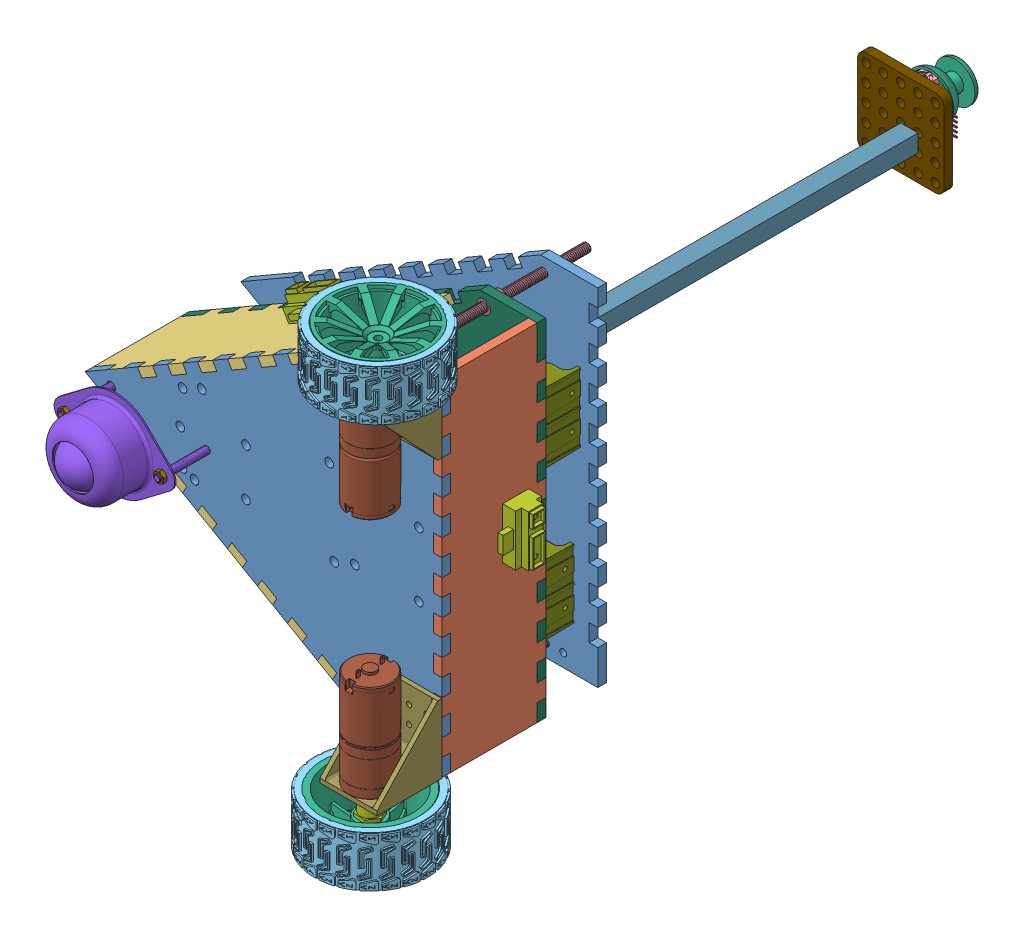
SolidWorks assembly Assembly File_R01, configuration Default. Lengths in mm.
Overall size (224.4 260.03 452.74).
51 component instances, 27 part files, 75 mates.
Components (placement in the parent):
- triangular base 1-1: triangular base 1 [Default] at (154.8111 203.7551 170.4098) size (206.21 200 5)
- the back wall-1: the back wall [Default] at (152.3111 203.7551 170.4098) x (1 0 0) z (0 1 0) size (5 60 200)
- Walls-1: Walls [Default] at (-31.5732 93.7549 170.4098) x (0.866025 -0.5 0) z (0.5 0.866025 0) size (180 60 5)
- Walls-2: Walls [Default] at (-46.394 99.4249 170.4098) x (0.866025 0.5 0) z (-0.5 0.866025 0) size (180 60 5)
- ArduinoMega2560-1: ArduinoMega2560 [Predeterminado] at (124.9198 138.7551 169.4098) x (0 1 0) z (-1 0 0) size (100 11.65 51.63)
- blue_wheel_with_adapter-1: blue_wheel_with_adapter [Default] at (122.4376 180.4937 248.1171) x (1 0 0) z (0 1 0) size (69.31 69.31 29.8)
  - 65mm tire-1: 65mm tire [Default] at (18.1044 52.2783 38.5614) x (-0.068419 0.997657 0) z (0 0 1) size (65.01 65.01 29)
  - blue_wheel_frame-2: blue_wheel_frame [Default] at (18.0756 52.6985 38.5614) x (0 0 -1) z (-0.994893 -0.10093 0) size (29 56 56)
  - motor_adapter-1: motor_adapter [Default] at (18.0661 52.7117 35.2614) x (0.583313 -0.812247 0) z (0 0 1) size (13.7 12 18.23)
- blue_wheel_with_adapter-2: blue_wheel_with_adapter [Default] at (122.7449 26.5815 147.6981) x (1 0 0) z (0 -1 0) size (69.31 69.31 29.8)
  - 65mm tire-1: 65mm tire [Default] at (18.1044 52.2783 38.5614) x (-0.068419 0.997657 0) z (0 0 1) size (65.01 65.01 29)
  - blue_wheel_frame-2: blue_wheel_frame [Default] at (18.0756 52.6985 38.5614) x (0 0 -1) z (-0.994893 -0.10093 0) size (29 56 56)
  - motor_adapter-1: motor_adapter [Default] at (18.0661 52.7117 35.2614) x (0.583313 -0.812247 0) z (0 0 1) size (13.7 12 18.23)
- Flange-Mount Ball Transfer-1: Flange-Mount Ball Transfer [Default] at (-6.1792 101.835 201.1718) x (0.069114 0.997609 0) z (-0.997609 0.069114 0) size (50.8 30.16 69.85)
- l298n1-1: l298n1 [Default] at (23.2111 102.2551 170.4098) x (0 -1 0) z (0 0 -1) size (43 43 26.5)
- MiniBreadboard-1: MiniBreadboard [Default] at (129.5111 61.4551 170.4098) x (0 1 0) z (-1 0 0) size (34.6 8.15 45.6)
- JGA25-372 24V Motor-1: JGA25-372 24V Motor [Ratio 171 & 226] at (140.8111 5.8202 200.4098) x (0 0 -1) z (-1 0 0) size (25.02 71.1 25)
- JGA25-372 24V Motor-2: JGA25-372 24V Motor [Ratio 171 & 226] at (140.8111 201.2551 200.4098) x (0 0 1) z (-1 0 0) size (25.02 71.1 25)
- L HOLDER DC MOTOR-1: L HOLDER DC MOTOR [Default] at (126.8111 203.7551 175.4098) x (1 0 0) z (0 -1 0) size (33 37.5 40)
- L HOLDER DC MOTOR-2: L HOLDER DC MOTOR [Default] at (154.8111 3.3202 175.4098) x (-1 0 0) z (0 1 0) size (33 37.5 40)
- M5 x 50mm CAPHEAD BOLT-1: M5 x 50mm CAPHEAD BOLT [Default] at (126.3207 196.2551 120.4098) x (1 0 0) z (0 1 0) size (8.4 55.33 8.4)
- M5 x 50mm CAPHEAD BOLT-2: M5 x 50mm CAPHEAD BOLT [Default] at (126.3207 11.2551 125.4098) x (0.989821 -0.142315 0) z (0.142315 0.989821 0) size (8.4 55.33 8.4)
- IV Stand-1: IV Stand [Default] at (72.3111 103.7551 -179.5902) x (1 0 0) z (0 -1 0) size (10 350 10)
- 1st Layer-1: 1st Layer [Default] at (154.8111 203.7551 115.4098) size (206.21 200 5)
- Batt_Pack_Main-1: Batt_Pack_Main [Défaut] at (154.2111 147.821 115.4098) x (0 1 0) z (-1 0 0) size (40.4 21.36 77.92)
- Batt_Pack_Main-2: Batt_Pack_Main [Défaut] at (76.4911 57.8028 115.4252) x (0 -1 0) z (1 0 0) size (40.4 21.36 77.92)
- Batt_main-1: Batt_main [Défaut] at (84.3111 68.6601 104.2466) x (0 -1 0) z (0 0 1) size (18.2 64.88 18.2)
- Batt_main-2: Batt_main [Défaut] at (85.3311 156.921 103.6199) x (0 -0.98599 -0.166804) z (0 -0.166804 0.98599) size (18.2 64.88 18.2)
- Batt_main-5: Batt_main [Défaut] at (85.3311 138.721 103.6199) x (0 0.98599 -0.166804) z (0 -0.166804 -0.98599) size (18.2 64.88 18.2)
- Batt_main-6: Batt_main [Défaut] at (84.3111 46.9455 104.2466) x (0 1 0) z (0 0 -1) size (18.2 64.88 18.2)
- M5 x 50mm CAPHEAD BOLT-5: M5 x 50mm CAPHEAD BOLT [Default] at (126.3207 196.2551 110.4098) x (1 0 0) z (0 -1 0) size (8.4 55.33 8.4)
- Addational useful layer 2-1: Addational useful layer 2 [Default] at (67.3111 108.7551 -179.5902) x (1 0 0) z (0 1 0) size (50 5 50)
- Top layer-1: Top layer [Default] at (154.8111 3.7551 85.4098) x (1 0 0) z (0 0 -1) size (206.21 200 5)
- Joystick assembly-1: Joystick assembly [Default] at (82.3111 123.7551 -186.0902) x (0 -1 0) z (1 0 0) size (30.12 34.52 39.55)
  - board-1: board [Default] at origin size (26.4 6.02 39.55)
  - Thumb Joystick-1: Thumb Joystick [기본] at (15.2543 37 -18.0537) x (1 0 0) z (0 -1 0) size (30.12 30.12 34.52)
    - body-1: body [기본] at (-10.9543 -7.0963 23.5) size (22.1 16 23.5)
    - potentiometer-1: potentiometer [기본] at (-2.9543 -7.0963 29) x (-1 0 0) z (0 -1 0) size (9.5 14.5 3.5)
    - potentiometer-2: potentiometer [기본] at (-10.9543 0.9037 29.5) x (0 1 0) z (-1 0 0) size (9.5 14.5 3.5)
    - tactileswitch-short-1: tactileswitch-short [Default] at (7.6493 0.9037 34) x (0 -1 0) z (1 0 0) size (6.89 8.33 6.01)
    - joystickhead-1: joystickhead [기본] at (-21.7711 -52.5336 38.75) x (0.118335 0.992974 0) z (0 0 -1) size (27.11 27.11 19.35)
- sharp 2y0a21 f 21-4: sharp 2y0a21 f 21 [Standard] at (157.3111 123.2551 140.4098) x (0 -1 0) z (0 0 1) size (29.5 13.5 21)
- sharp 2y0a21 f 21-5: sharp 2y0a21 f 21 [Standard] at (33.8114 151.5051 140.4098) x (0.866025 0.5 0) z (0 0 1) size (29.5 13.5 21)
- sharp 2y0a21 f 21-6: sharp 2y0a21 f 21 [Standard] at (59.6596 41.0816 140.4098) x (-0.866025 0.5 0) z (0 0 1) size (29.5 13.5 21)
- M5 x 50mm CAPHEAD BOLT-6: M5 x 50mm CAPHEAD BOLT [Default] at (126.3207 11.2551 110.4098) x (1 0 0) z (0 -1 0) size (8.4 55.33 8.4)
- M4 x 50mm CAPHEAD BOLT-3: M4 x 50mm CAPHEAD BOLT [Default] at (-33.894 103.7551 152.4098) x (0.930623 0.365979 0) z (0 0 -1) size (7 7 57.92)
- hex nut style 1_am-1: hex nut style 1_am [B18.2.4.1M - Hex nut, Style 1,  M3 x 0.5 --D-N] at (-33.894 103.7551 203.5718) size (5.5 6.35 2.4)
- hex nut style 1_am-2: hex nut style 1_am [B18.2.4.1M - Hex nut, Style 1,  M3 x 0.5 --D-N] at (126.3207 196.2551 78.0098) x (0.923728 0.383049 0) z (0 0 -1) size (5.5 6.35 2.4)
- hex nut style 1_am-3: hex nut style 1_am [B18.2.4.1M - Hex nut, Style 1,  M3 x 0.5 --D-N] at (126.3207 11.2551 78.0098) x (0.923728 0.383049 0) z (0 0 -1) size (5.5 6.35 2.4)
- M4 x 50mm CAPHEAD BOLT-5: M4 x 50mm CAPHEAD BOLT [Default] at (21.5356 99.9149 152.4098) x (0.871265 -0.490813 0) z (0 0 -1) size (7 7 57.92)
- hex nut style 1_am-4: hex nut style 1_am [B18.2.4.1M - Hex nut, Style 1,  M3 x 0.5 --D-N] at (21.5356 99.9149 201.1718) x (-0.990447 0.137897 0) z (0 0 -1) size (5.5 6.35 2.4)
Mates (geometry in assembly coordinates):
- Coincident3: coincident anti-aligned: plane of triangular base 1-1 through (154.8111 203.7551 175.4098) normal (0 0 1); plane of L HOLDER DC MOTOR-2 through (126.8111 43.3202 175.4098) normal (0 0 -1)
- Coincident5: coincident anti-aligned: plane of triangular base 1-1 through (154.8111 203.7551 175.4098) normal (0 0 1); plane of L HOLDER DC MOTOR-1 through (154.8111 163.7551 175.4098) normal (0 0 -1)
- Concentric6: concentric aligned: cylinder of JGA25-372 24V Motor-2 through (149.3111 201.2551 200.4098) axis (0 1 0) radius 1.25; cylinder of L HOLDER DC MOTOR-1 through (149.3111 163.7551 200.4098) axis (0 1 0) radius 1.5
- Concentric7: concentric anti-aligned: cylinder of JGA25-372 24V Motor-2 through (140.8111 218.4119 200.4098) axis (0 -1 0) radius 2; cylinder of L HOLDER DC MOTOR-1 through (140.8111 163.7551 200.4098) axis (0 1 0) radius 3.75
- Coincident7: coincident anti-aligned: plane of JGA25-372 24V Motor-1 through (140.8111 5.8202 200.4098) normal (0 -1 0); plane of L HOLDER DC MOTOR-2 through (126.8111 5.8202 212.9098) normal (0 1 0)
- Concentric8: concentric aligned: cylinder of JGA25-372 24V Motor-1 through (149.3111 5.8202 200.4098) axis (0 -1 0) radius 1.25; cylinder of L HOLDER DC MOTOR-2 through (149.3111 43.3202 200.4098) axis (0 -1 0) radius 1.5
- Concentric9: concentric aligned: cylinder of JGA25-372 24V Motor-1 through (132.3111 5.8202 200.4098) axis (0 -1 0) radius 1.25; cylinder of L HOLDER DC MOTOR-2 through (132.3111 43.3202 200.4098) axis (0 -1 0) radius 1.5
- Coincident13: coincident aligned: line of triangular base 1-1 through (-48.894 103.7551 170.4098) axis (0.866025 0.5 0); line of Walls-2 through (-48.894 103.7551 170.4098) axis (0.866025 0.5 0)
- Coincident14: coincident aligned: line of triangular base 1-1 through (-48.894 103.7551 175.4098) axis (0 0 -1); line of Walls-2 through (-48.894 103.7551 170.4098) axis (0 0 -1)
- Coincident19: coincident aligned: line of triangular base 1-1 through (157.3111 203.7551 170.4098) axis (-1 0 0); line of the back wall-1 through (157.3111 203.7551 170.4098) axis (-1 0 0)
- Coincident20: coincident: moEndPointRef_w of triangular base 1-1; line of the back wall-1 through (157.3111 203.7551 120.4098) axis (0 0 1)
- Coincident26: coincident anti-aligned: plane of the back wall-1 through (152.3111 203.7551 170.4098) normal (-1 0 0); plane of MiniBreadboard-1 through (152.3111 44.1551 162.2598) normal (1 0 0)
- Coincident27: coincident aligned: plane of triangular base 1-1 through (154.8111 203.7551 175.4098) normal (0 1 0); plane of L HOLDER DC MOTOR-1 through (154.8111 203.7551 175.4098) normal (0 1 0)
- Concentric16: concentric anti-aligned: cylinder of blue_wheel_with_adapter-2/motor_adapter-1 through (140.8111 3.3202 200.4098) axis (0 -1 0) radius 5.5; cylinder of JGA25-372 24V Motor-1 through (140.8111 -11.3367 200.4098) axis (0 1 0) radius 2
- Coincident30: coincident anti-aligned: plane of blue_wheel_with_adapter-2/motor_adapter-1 through (140.8111 3.3202 200.4098) normal (0 1 0); plane of L HOLDER DC MOTOR-2 through (126.8111 3.3202 175.4098) normal (0 -1 0)
- Distance19: distance = 2 mm aligned: plane of ArduinoMega2560-1 through (124.9198 138.7551 168.4098) normal (0 0 -1); plane of triangular base 1-1 through (154.8111 203.7551 170.4098) normal (0 0 -1)
- Distance20: distance = 15 mm aligned: plane of ArduinoMega2560-1 through (98.4198 188.7551 168.4098) normal (0 1 0); plane of triangular base 1-1 through (154.8111 203.7551 175.4098) normal (0 1 0)
- Distance21: distance = 2 mm anti-aligned: plane of ArduinoMega2560-1 through (150.3111 188.7551 178.4098) normal (1 0 0); plane of the back wall-1 through (152.3111 203.7551 170.4098) normal (-1 0 0)
- Distance22: distance = 0 mm anti-aligned: plane of MiniBreadboard-1 through (106.7111 78.7551 170.4098) normal (0 0 1); plane of triangular base 1-1 through (154.8111 203.7551 170.4098) normal (0 0 -1)
- Distance23: distance = 10 mm anti-aligned: plane of MiniBreadboard-1 through (152.3111 78.7551 162.2598) normal (0 1 0); plane of ArduinoMega2560-1 through (98.4198 88.7551 168.4098) normal (0 -1 0)
- Coincident47: coincident aligned: plane of triangular base 1-1 through (154.8111 203.7551 170.4098) normal (0 0 -1); plane of l298n1-1 through (23.2111 102.2551 170.4098) normal (0 0 -1)
- Distance26: distance = 105 mm anti-aligned: plane of l298n1-1 through (1.7111 80.7551 170.4098) normal (1 0 0); plane of MiniBreadboard-1 through (106.7111 44.1551 162.2598) normal (-1 0 0)
- Distance27: distance = 80 mm anti-aligned: plane of triangular base 1-1 through (154.8111 203.7551 175.4098) normal (0 1 0); plane of l298n1-1 through (1.7111 123.7551 170.4098) normal (0 -1 0)
- Distance28: distance = 0 mm aligned: plane of Walls-1 through (-29.0732 98.085 175.4098) normal (0 0 1); plane of triangular base 1-1 through (154.8111 203.7551 175.4098) normal (0 0 1)
- Distance29: distance = -2000 mm anti-aligned: plane of triangular base 1-1 through (27.2181 65.5852 170.4098) normal (-0.5 -0.866025 0); plane of Walls-1 through (-29.0732 98.085 170.4098) normal (0.5 0.866025 0)
- Concentric18: concentric aligned: cylinder of triangular base 1-1 through (126.3207 196.2551 170.4098) axis (0 0 1) radius 2.5; cylinder of M5 x 50mm CAPHEAD BOLT-1 through (126.3207 196.2551 115.4098) axis (0 0 1) radius 4.2
- Coincident54: coincident aligned: plane of triangular base 1-1 through (157.3111 203.7551 175.4098) normal (1 0 0); plane of L HOLDER DC MOTOR-1 through (157.3111 203.7551 175.4098) normal (1 0 0)
- Distance36: distance = 0 mm: cylinder of blue_wheel_with_adapter-1/motor_adapter-1 through (140.5132 215.7551 195.4186) axis (0 -1 0) radius 3; cylinder of JGA25-372 24V Motor-2 through (140.8111 218.4119 200.4098) axis (0 -1 0) radius 2
- Distance37: distance = 0 mm anti-aligned: plane of blue_wheel_with_adapter-1/motor_adapter-1 through (140.5038 203.7551 195.4054) normal (0 -1 0); plane of L HOLDER DC MOTOR-1 through (154.8111 203.7551 175.4098) normal (0 1 0)
- Distance42: distance = 50 mm aligned: plane of M5 x 50mm CAPHEAD BOLT-2 through (126.3207 11.2551 120.4098) normal (0 0 -1); plane of triangular base 1-1 through (154.8111 203.7551 170.4098) normal (0 0 -1)
- Concentric23: concentric anti-aligned: circle of triangular base 1-1; circle of M5 x 50mm CAPHEAD BOLT-2
- Distance44: distance = 0 mm anti-aligned: plane of IV Stand-1 through (72.3111 103.7551 170.4098) normal (0 0 1); plane of triangular base 1-1 through (154.8111 203.7551 170.4098) normal (0 0 -1)
- Distance45: distance = 80 mm aligned: plane of IV Stand-1 through (77.3111 108.7551 170.4098) normal (1 0 0); plane of the back wall-1 through (157.3111 203.7551 170.4098) normal (1 0 0)
- Distance46: distance = 95 mm aligned: plane of IV Stand-1 through (67.3111 108.7551 170.4098) normal (0 1 0); plane of the back wall-1 through (157.3111 203.7551 170.4098) normal (0 1 0)
- Coincident71: coincident aligned: plane of the back wall-1 through (157.3111 203.7551 170.4098) normal (1 0 0); plane of 1st Layer-1 through (157.3111 203.7551 120.4098) normal (1 0 0)
- Distance56: distance = 0 mm aligned: plane of 1st Layer-1 through (154.8111 3.7551 120.4098) normal (0 -1 0); plane of triangular base 1-1 through (154.8111 3.7551 175.4098) normal (0 -1 0)
- Coincident74: coincident anti-aligned: plane of the back wall-1 through (157.3111 203.7551 120.4098) normal (0 0 -1); plane of 1st Layer-1 through (154.8111 203.7551 120.4098) normal (0 0 1)
- Distance62: distance = 1 mm aligned: plane of Batt_Pack_Main-1 through (156.3111 147.821 115.4098) normal (1 0 0); plane of the back wall-1 through (157.3111 203.7551 170.4098) normal (1 0 0)
- Distance70: distance = 90 mm aligned: plane of Batt_Pack_Main-2 through (150.2111 77.9945 115.0159) normal (0 0.999795 -0.020266); plane of Batt_Pack_Main-1 through (80.4911 168.0127 115.0005) normal (0 0.999795 -0.020266)
- Distance71: distance = 5 mm aligned: plane of Batt_Pack_Main-2 through (152.3111 57.8028 115.4252) normal (1 0 0); plane of the back wall-1 through (157.3111 203.7551 170.4098) normal (1 0 0)
- Tangent3: tangent anti-aligned: unknown of Batt_Pack_Main-1; cylinder of Batt_main-2 through (85.3311 156.921 103.6199) axis (-1 0 0) radius 9.1
- Coincident95: coincident anti-aligned: plane of Batt_Pack_Main-1 through (150.2111 147.821 98.6698) normal (-1 0 0); plane of Batt_main-2 through (150.2111 156.921 103.6199) normal (1 0 0)
- Coincident96: coincident anti-aligned: plane of Batt_Pack_Main-1 through (84.4911 147.821 98.6698) normal (1 0 0); plane of Batt_main-1 through (84.4911 61.6601 104.2466) normal (-1 0 0)
- Parallel19: parallel aligned: cylinder of Batt_main-1 through (84.3111 68.6601 104.2466) axis (-1 0 0) radius 9.1; cylinder of Batt_main-2 through (85.3311 156.921 103.6199) axis (-1 0 0) radius 9.1
- Parallel21: parallel anti-aligned: plane of Batt_Pack_Main-2 through (146.2111 57.8028 98.6852) normal (-1 0 0); plane of Batt_main-1 through (149.1911 68.6601 104.2466) normal (1 0 0)
- Coincident97: coincident anti-aligned: plane of IV Stand-1 through (72.3111 103.7551 -179.5902) normal (0 0 -1); plane of Addational useful layer 2-1 through (87.3111 88.7551 -179.5902) normal (0 0 1)
- Distance73: distance = 25 mm aligned: plane of IV Stand-1 through (67.3111 108.7551 170.4098) normal (0 1 0); plane of Addational useful layer 2-1 through (87.3111 133.7551 -184.5902) normal (0 1 0)
- Distance72: distance = 25 mm aligned: plane of Addational useful layer 2-1 through (42.3111 128.7551 -184.5902) normal (-1 0 0); plane of IV Stand-1 through (67.3111 108.7551 170.4098) normal (-1 0 0)
- Coincident101: coincident aligned: plane of 1st Layer-1 through (154.8111 203.7551 120.4098) normal (0 1 0); plane of Top layer-1 through (154.8111 203.7551 80.4098) normal (0 1 0)
- Coincident103: coincident aligned: plane of the back wall-1 through (157.3111 203.7551 170.4098) normal (1 0 0); plane of Top layer-1 through (157.3111 3.7551 80.4098) normal (1 0 0)
- Distance74: distance = 35 mm aligned: plane of Top layer-1 through (154.8111 3.7551 80.4098) normal (0 0 -1); plane of 1st Layer-1 through (154.8111 203.7551 115.4098) normal (0 0 -1)
- Distance77: distance = 3 mm: plane of Addational useful layer 2-1 through (87.3111 88.7551 -184.5902) normal (0 0 -1); line of Joystick assembly-1/Thumb Joystick-1/body-1 through (73.1611 105.1551 -187.5902) axis (0 1 0)
- Distance82: distance = 10 mm aligned: plane of Addational useful layer 2-1 through (92.3111 128.7551 -184.5902) normal (1 0 0); plane of Joystick assembly-1/board-1 through (82.3111 123.7551 -187.5902) normal (1 0 0)
- Distance83: distance = 10 mm aligned: plane of Joystick assembly-1/board-1 through (82.3111 123.7551 -187.5902) normal (0 1 0); plane of Addational useful layer 2-1 through (87.3111 133.7551 -184.5902) normal (0 1 0)
- Coincident118: coincident anti-aligned: plane of Walls-2 through (-48.894 103.7551 170.4098) normal (-0.5 0.866025 0); plane of sharp 2y0a21 f 21-5 through (33.8114 151.5051 125.4098) normal (0.5 -0.866025 0)
- Distance84: distance = 55 mm aligned: plane of Walls-2 through (106.9905 193.7551 170.4098) normal (0.866025 0.5 0); plane of sharp 2y0a21 f 21-5 through (55.6091 172.7503 140.4098) normal (0.866025 0.5 0)
- Distance85: distance = 10 mm aligned: plane of 1st Layer-1 through (154.8111 203.7551 115.4098) normal (0 0 -1); plane of sharp 2y0a21 f 21-5 through (30.0614 158.0003 125.4098) normal (0 0 -1)
- Coincident121: coincident anti-aligned: plane of Walls-1 through (-31.5732 93.7549 170.4098) normal (-0.5 -0.866025 0); plane of sharp 2y0a21 f 21-6 through (59.6596 41.0816 125.4098) normal (0.5 0.866025 0)
- Distance88: distance = 10 mm aligned: plane of sharp 2y0a21 f 21-6 through (55.9096 34.5864 125.4098) normal (0 0 -1); plane of 1st Layer-1 through (154.8111 203.7551 115.4098) normal (0 0 -1)
- Coincident126: coincident anti-aligned: plane of the back wall-1 through (157.3111 203.7551 170.4098) normal (1 0 0); plane of sharp 2y0a21 f 21-4 through (157.3111 123.2551 125.4098) normal (-1 0 0)
- Distance89: distance = 10 mm aligned: plane of sharp 2y0a21 f 21-4 through (164.8111 123.2551 125.4098) normal (0 0 -1); plane of 1st Layer-1 through (154.8111 203.7551 115.4098) normal (0 0 -1)
- Distance90: distance = 90 mm aligned: plane of the back wall-1 through (157.3111 3.7551 170.4098) normal (0 -1 0); plane of sharp 2y0a21 f 21-4 through (164.8111 93.7551 140.4098) normal (0 -1 0)
- Distance94: distance = 0 mm anti-aligned: plane of Batt_Pack_Main-1 through (80.4911 147.821 115.4098) normal (0 0 1); plane of 1st Layer-1 through (154.8111 203.7551 115.4098) normal (0 0 -1)
- Distance95: distance = 0 mm anti-aligned: plane of M5 x 50mm CAPHEAD BOLT-5 through (126.3207 196.2551 115.4098) normal (0 0 1); plane of 1st Layer-1 through (154.8111 203.7551 115.4098) normal (0 0 -1)
- Parallel25: parallel aligned: cylinder of Batt_main-1 through (84.3111 68.6601 104.2466) axis (-1 0 0) radius 9.1; cylinder of Batt_main-2 through (85.3311 156.921 103.6199) axis (-1 0 0) radius 9.1
- Distance96: distance = 20 mm aligned: plane of M4 x 50mm CAPHEAD BOLT-3 through (-33.894 103.7551 150.4098) normal (0 0 -1); plane of triangular base 1-1 through (154.8111 203.7551 170.4098) normal (0 0 -1)
- Distance98: distance = 25 mm anti-aligned: plane of Flange-Mount Ball Transfer-1 through (-6.1792 101.835 200.4098) normal (0 0 -1); plane of triangular base 1-1 through (154.8111 203.7551 175.4098) normal (0 0 1)
- Concentric27: concentric aligned: cylinder of triangular base 1-1 through (-33.894 103.7551 170.4098) axis (0 0 1) radius 2.5; cylinder of M4 x 50mm CAPHEAD BOLT-3 through (-33.894 103.7551 150.4098) axis (0 0 1) radius 3.5
- Concentric28: concentric anti-aligned: circle of triangular base 1-1; circle of Flange-Mount Ball Transfer-1
- Concentric29: concentric anti-aligned: cylinder of M4 x 50mm CAPHEAD BOLT-3 through (-33.894 103.7551 204.4098) axis (0 0 -1) radius 2; cylinder of hex nut style 1_am-1 through (-33.894 103.7551 201.1718) axis (0 0 1) radius 1.25
- Coincident138: coincident anti-aligned: plane of Flange-Mount Ball Transfer-1 through (-6.1792 101.835 201.1718) normal (0 0 1); plane of hex nut style 1_am-1 through (-39.394 103.7551 201.1718) normal (0 0 -1)
- Coincident139: coincident anti-aligned: plane of Top layer-1 through (154.8111 3.7551 80.4098) normal (0 0 -1); plane of hex nut style 1_am-2 through (121.2402 194.1483 80.4098) normal (0 0 1)
- Concentric30: concentric aligned: circle of M5 x 50mm CAPHEAD BOLT-5; cylinder of hex nut style 1_am-2 through (126.3207 196.2551 80.4098) axis (0 0 -1) radius 1.25
- Coincident140: coincident anti-aligned: plane of Top layer-1 through (154.8111 3.7551 80.4098) normal (0 0 -1); plane of hex nut style 1_am-3 through (121.2402 9.1483 80.4098) normal (0 0 1)
- Concentric31: concentric aligned: circle of M5 x 50mm CAPHEAD BOLT-6; cylinder of hex nut style 1_am-3 through (126.3207 11.2551 80.4098) axis (0 0 -1) radius 1.25
